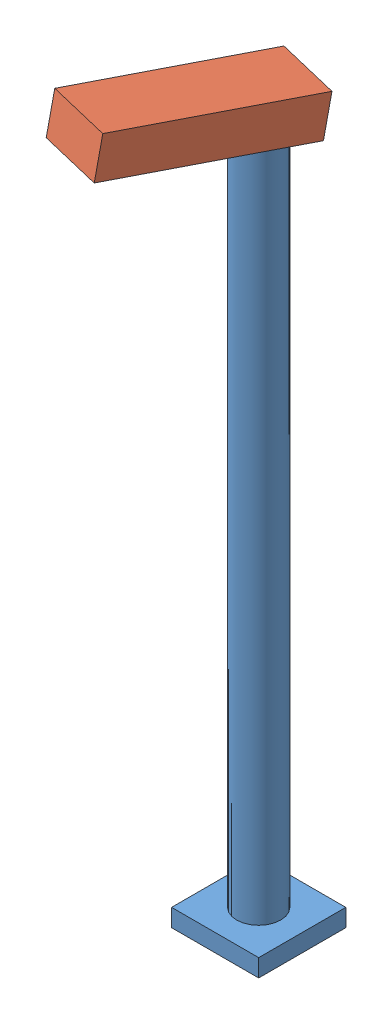
SolidWorks assembly Assem1, configuration Default. Lengths in mm.
Overall size (20.27 138.3 37.52).
2 component instances, 2 part files, 2 mates.
Components (placement in the parent):
- 2x2-1: 2x2 [Lamp post] at origin size (15.8 131.2 15.8)
- light-top-1: light-top [Default] at (-4.718 129.5722 19.6098) x (0.972256 0 0.233919) z (-0.230365 0.173648 0.957485) size (11.8 7.4 35)
Mates (geometry in assembly coordinates):
- Concentric1: concentric: cylinder of 2x2-1 through (0 131.2 0) axis (0 -1 0) radius 4; cylinder of light-top-1 through (0 155.8614 0) axis (0 -1 0) radius 4.125
- Tangent1: tangent: circle of 2x2-1; plane of light-top-1 through (-4.4824 135.2841 18.6306) normal (-0.04062 -0.984808 0.16883)
